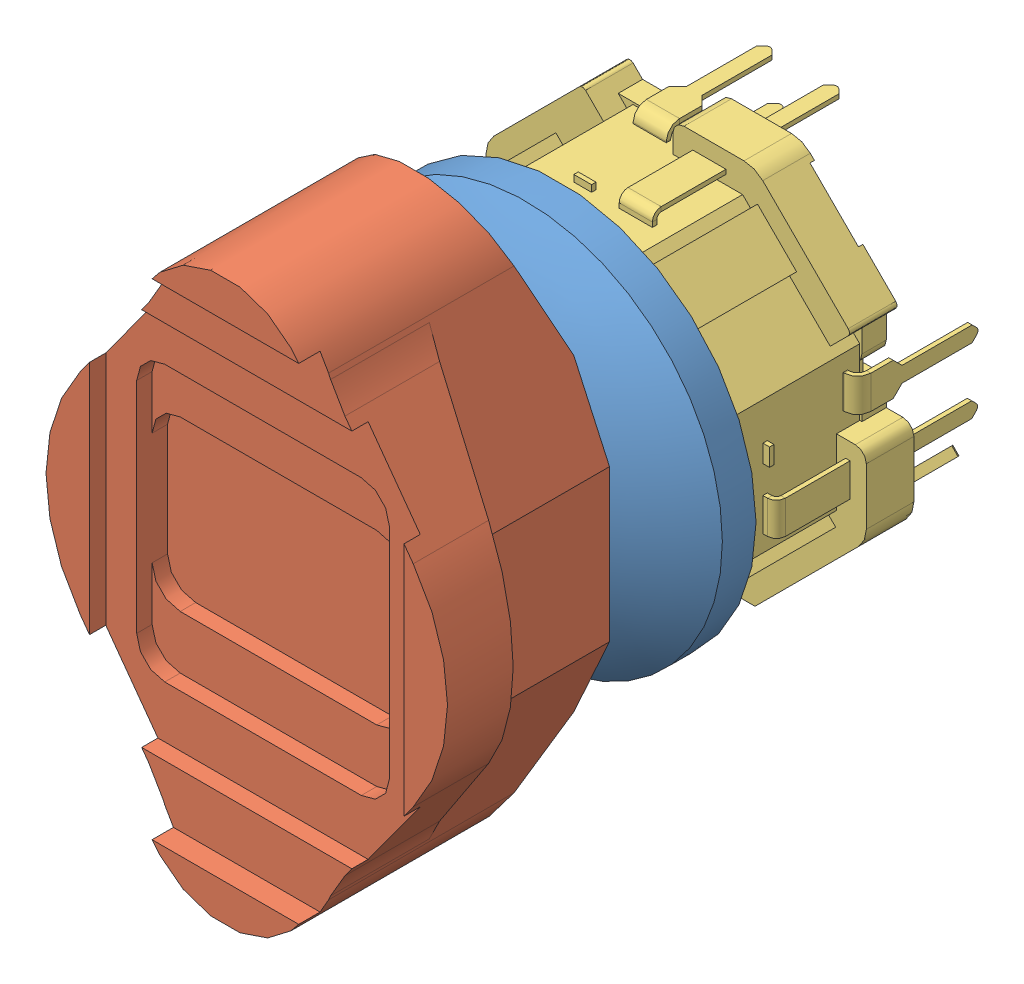
SolidWorks assembly COMM 4-WAY SWITCH, configuration Default. Lengths in mm.
Overall size (18.16 25.4 26.16).
3 component instances, 3 part files, 3 mates.
Components (placement in the parent):
- COMM 4-WAY Switch Body-1: COMM 4-WAY Switch Body [Default] at origin size (17.78 17.78 4.21)
- COMM 4-WAY Switch Hat-1: COMM 4-WAY Switch Hat [Default] at origin size (18.16 25.4 10.54)
- RKJXT1F42001-1: RKJXT1F42001 [Default] at (0 0 1.1636) size (17.2 17.2 20.62)
Mates (geometry in assembly coordinates):
- Parallel1: parallel: plane of COMM 4-WAY Switch Hat-1 through (-3.316 10.9855 24.1046) normal (0 -1 0); plane of RKJXT1F42001-1 through (-1.1225 0.55 13.5636) normal (0 1 0)
- Concentric2: concentric: cylinder of COMM 4-WAY Switch Body-1 through (0 0 9.7536) axis (0 0 1) radius 8.89; cylinder of RKJXT1F42001-1 through (0 0 -1.9887) axis (0 0 -1) radius 1.25
- Coincident2: coincident: plane of COMM 4-WAY Switch Hat-1 through (0 0 13.5636) normal (0 0 -1); plane of RKJXT1F42001-1 through (0 0 13.5636) normal (0 0 1)
